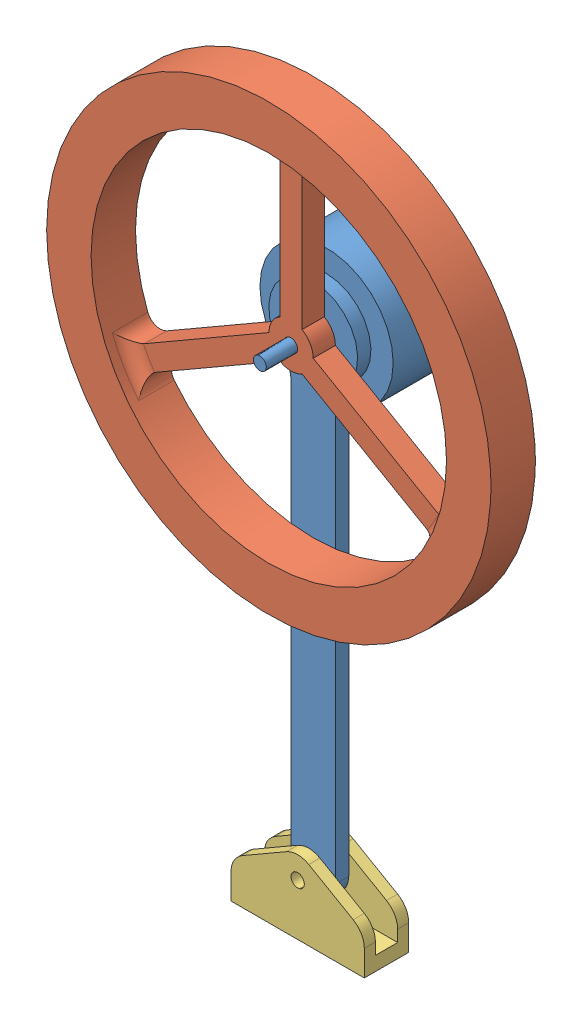
SolidWorks assembly Assem1, configuration Default. Lengths in mm.
Overall size (100 166.55 30).
3 component instances, 3 part files, 4 mates.
Components (placement in the parent):
- react_arm-1: react_arm [Default] at origin size (30 125 30)
- react_wheel-1: react_wheel [Default] at (0 0 18) size (100 100 22.31)
- react_stand-1: react_stand [Default] at (0 -116.547 16.5) size (30 16.55 10)
Mates (geometry in assembly coordinates):
- Concentric1: concentric: cylinder of react_arm-1 through (0 0 30) axis (0 0 -1) radius 1.45; cylinder of react_wheel-1 through (0 0 18) axis (0 0 1) radius 1.5
- Coincident1: coincident anti-aligned: plane of react_arm-1 through (0 0 18) normal (0 0 1); plane of react_wheel-1 through (0 0 18) normal (0 0 -1)
- Concentric2: concentric: cylinder of react_arm-1 through (0 -105 0) axis (0 0 1) radius 1.5; cylinder of react_stand-1 through (0 -105 10.5) axis (0 0 1) radius 1.5
- Distance1: distance = 1 mm anti-aligned: plane of react_arm-1 through (0 0 18) normal (0 0 1); plane of react_stand-1 through (-15 -86.618 19) normal (0 0 -1)
